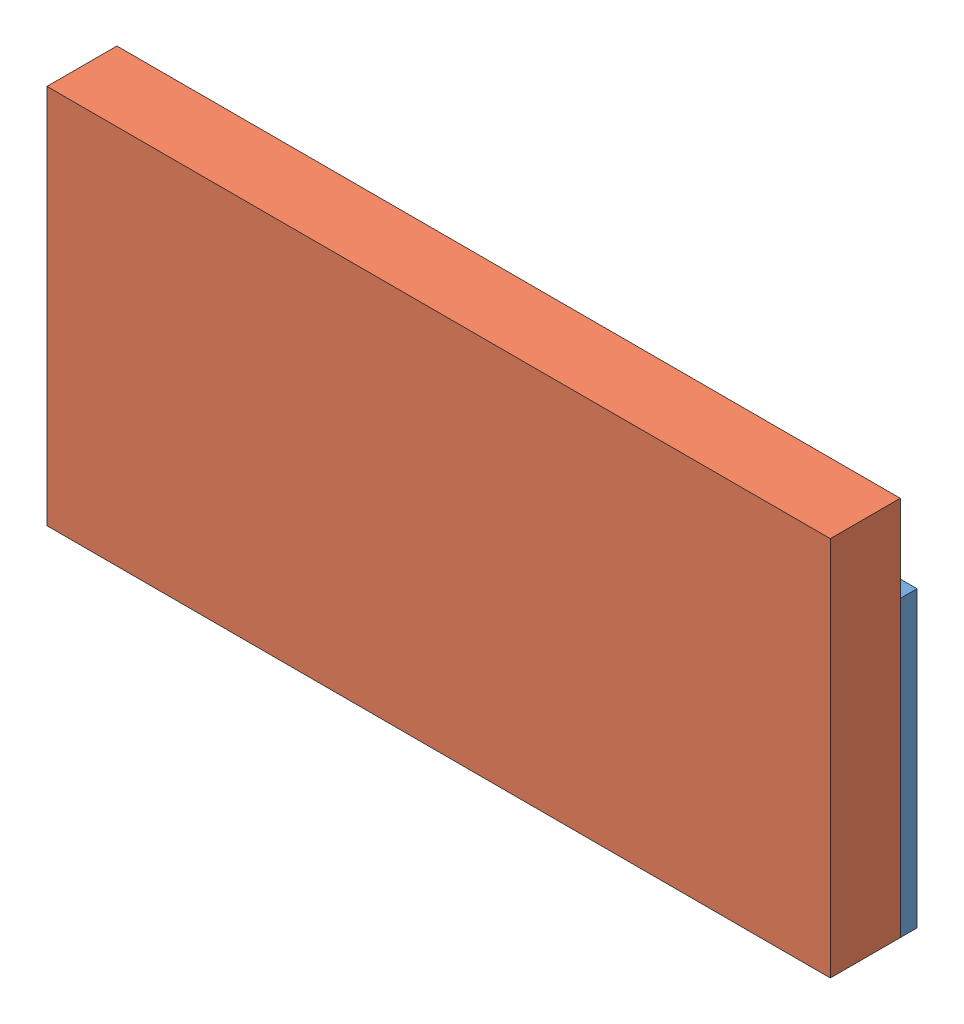
SolidWorks assembly Assem1, configuration Default. Lengths in mm.
Overall size (280 136 31).
2 component instances, 2 part files, 3 mates.
Components (placement in the parent):
- Door upper acry in-1: Door upper acry in [Default] at (56.4 157.9275 232.2921) size (280 105 6)
- Door upper poly-1: Door upper poly [Default] at (56.4 157.9275 238.2921) size (280 136 25)
Mates (geometry in assembly coordinates):
- Coincident1: coincident: plane of Door upper acry in-1 through (-66.0901 98.709 238.2921) normal (0 -1 0); plane of Door upper poly-1 through (-66.0901 98.709 263.2921) normal (0 -1 0)
- Coincident2: coincident: plane of Door upper acry in-1 through (213.9099 203.709 238.2921) normal (1 0 0); plane of Door upper poly-1 through (213.9099 234.709 263.2921) normal (1 0 0)
- Coincident3: coincident: plane of Door upper acry in-1 through (56.4 157.9275 238.2921) normal (0 0 1); plane of Door upper poly-1 through (56.4 157.9275 238.2921) normal (0 0 -1)
